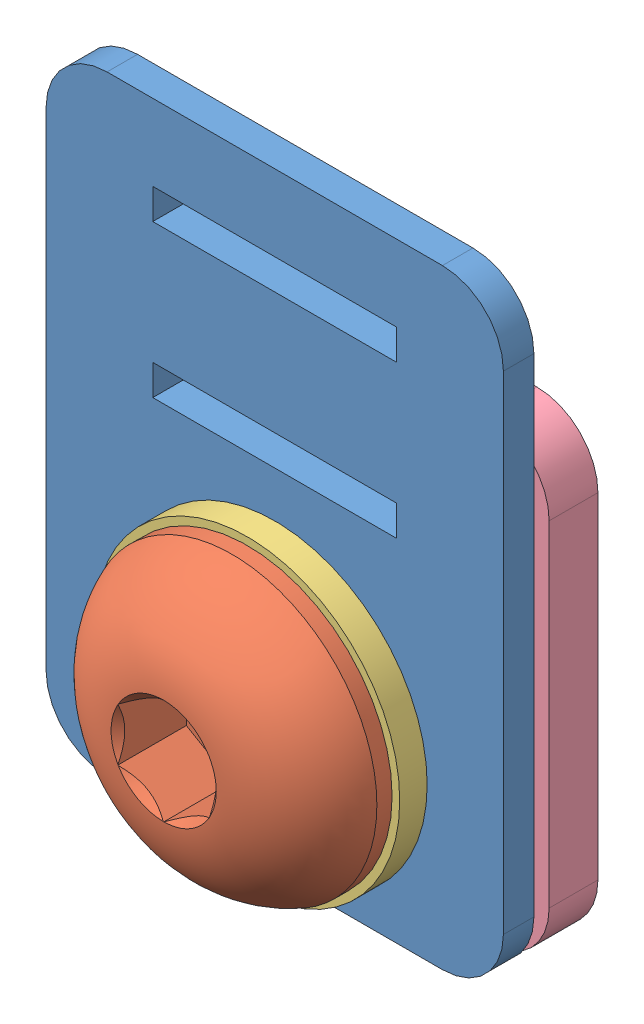
SolidWorks assembly belt_clip_assembly, configuration Default. Lengths in mm.
Overall size (15 22.5 10.91).
4 component instances, 4 part files, 9 mates.
Components (placement in the parent):
- 26051-01-1: 26051-01 [Default] at origin size (15 20 1)
- 91239A222-1: 91239A222 [Default] at (0 -5 -6.1) x (1 0 0) z (0 0 -1) size (9.5 9.5 10.91)
- 25287-02-1: 25287-02 [Default] at (0 -5 1.9) size (10 10 0.9)
- 26016-01-1: 26016-01 [Default] at (0 -5 -3) x (1 0 0) z (0 1 0) size (10 1.6 15)
Mates (geometry in assembly coordinates):
- Distance1: distance = 3 mm anti-aligned: plane of 26051-01-1 through (0 0 0) normal (0 0 -1); plane of 26016-01-1 through (0 -5 -3) normal (0 0 1)
- Concentric1: concentric aligned: cylinder of 26051-01-1 through (0 -5 1) axis (0 0 -1) radius 2.625; cylinder of 26016-01-1 through (0 -5 -3) axis (0 0 -1) radius 2.5
- Concentric2: concentric aligned: circle of 91239A222-1; cylinder of 25287-02-1 through (0 -5 1) axis (0 0 1) radius 2.65
- Coincident3: coincident anti-aligned: plane of 26051-01-1 through (0 0 1) normal (0 0 1); plane of 25287-02-1 through (0 -5 1) normal (0 0 -1)
- Coincident4: coincident anti-aligned: plane of 91239A222-1 through (0 -5 1.9) normal (0 0 -1); plane of 25287-02-1 through (0 -5 1.9) normal (0 0 1)
- Concentric3: concentric aligned: cylinder of 91239A222-1 through (0 -5 4.65) axis (0 0 -1) radius 4.75; cylinder of 26016-01-1 through (0 -5 -3) axis (0 0 -1) radius 2.5
- Parallel1: parallel aligned: plane of 26051-01-1 through (0 0 0) normal (1 0 0); plane of 26016-01-1
- Parallel2: parallel anti-aligned: plane of 91239A222-1 through (0 -5 -6.1) normal (0 -1 0); plane of assembly
- Parallel3: parallel anti-aligned: plane of 91239A222-1 through (0 -5 -6.1) normal (0 -1 0); plane of 25287-02-1 through (0 -5 1.9) normal (0 1 0)
